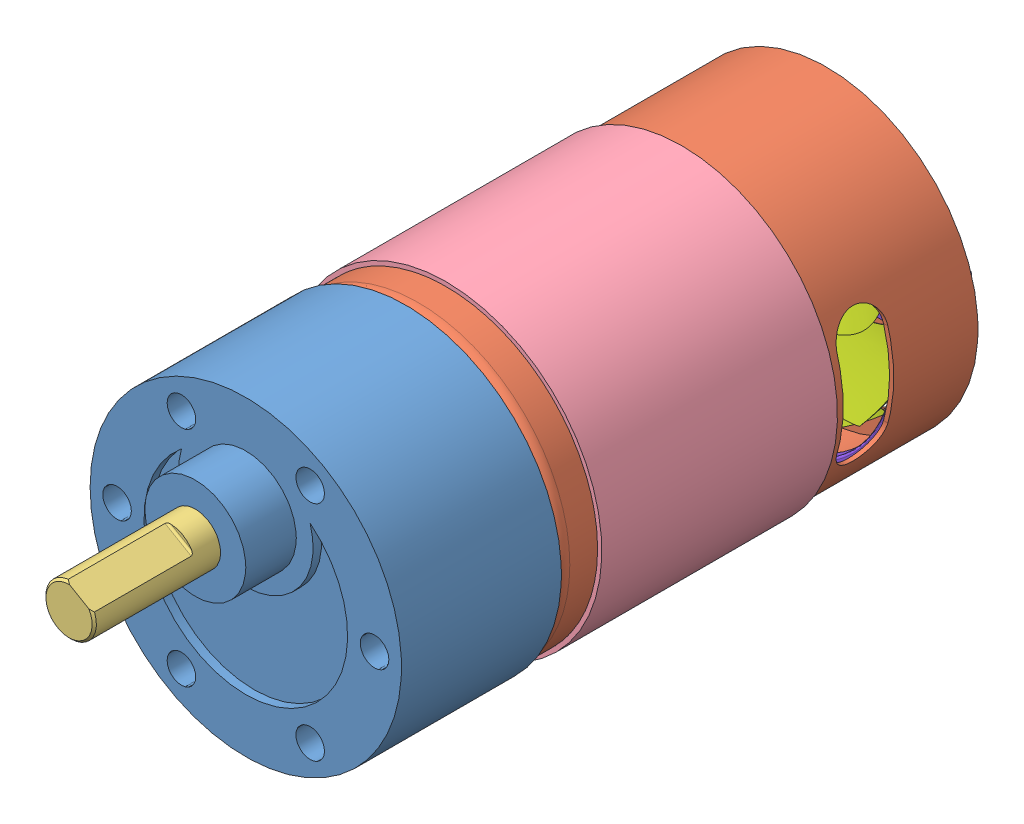
SolidWorks assembly Motor JGB37-545, configuration Predeterminado. Lengths in mm.
Overall size (41.44 41.14 94.88).
11 component instances, 11 part files, 33 mates.
Components (placement in the parent):
- Reduction box body-1: Reduction box body [Default] at (-12.375 1.5 54.875) size (37 37 25)
- Motor body-1: Motor body [Predeterminado] at (-12.375 1.5 4.875) size (36 36 52)
- Shaft-1: Shaft [Predeterminado] at (-12.375 8.5 67.775) x (0.863725 -0.503963 0) z (0 0 1) size (6 6 27.1)
- Cover-1: Cover [Predeterminado] at (-12.375 1.5 22.075) size (37 36.74 28)
- Rotor-1: Rotor [Predeterminado] at (-12.375 1.5 32.275) x (-0.951412 0.307919 0) z (0 0 1) size (26 25.6 60)
- Magnets-1: Magnets [Default] at (-12.375 1.5 22.875) x (0 1 0) z (0 0 1) size (35 27.22 20)
- Fan-1: Fan [Default] at (-12.375 1.5 12.975) x (-0.920955 0.389669 0) z (-0.389669 -0.920955 0) size (31.79 6.24 31.22)
- Terminals-1: Terminals [Default] at (-12.375 1.5 5.375) x (1 0 0) z (0 0 -1) size (34 34 22.88)
- Gear 1-1: Gear 1 [Default] at (-12.375 1.5 62.275) x (0.307919 0.951412 0) z (-0.951412 0.307919 0) size (5.97 2 5.97)
- Gear 2-1: Gear 2 [Default] at (-12.375 -3.65 64.275) x (0.994395 0.105729 0) z (-0.105729 0.994395 0) size (20 8.6 20)
- Gear 3-1: Gear 3 [Default] at (-12.375 8.5 66.275) x (-0.503963 -0.863725 0) z (0.863725 -0.503963 0) size (10 10 9.98)
Mates (geometry in assembly coordinates):
- Coincidente1: coincident anti-aligned: plane of Reduction box body-1 through (-12.375 1.5 54.875) normal (0 0 -1); plane of Motor body-1 through (-12.375 1.5 54.875) normal (0 0 1)
- Concéntrica1: concentric aligned: cylinder of Reduction box body-1 through (-12.375 1.5 73.875) axis (0 0 -1) radius 18.5; cylinder of Motor body-1 through (-12.375 1.5 54.875) axis (0 0 -1) radius 18
- Distancia1: distance = 15 mm aligned: plane of Shaft-1 through (-12.375 8.5 94.875) normal (0 0 1); plane of Reduction box body-1 through (-12.375 8.5 79.875) normal (0 0 1)
- Concéntrica2: concentric anti-aligned: cylinder of Reduction box body-1 through (-12.375 8.5 54.874) axis (0 0 1) radius 3; cylinder of Shaft-1 through (-12.375 8.5 94.875) axis (0 0 -1) radius 3
- Distancia2: distance = 4.8 mm anti-aligned: plane of Cover-1 through (-12.375 1.5 50.075) normal (0 0 1); plane of Reduction box body-1 through (-12.375 1.5 54.875) normal (0 0 -1)
- Concéntrica3: concentric aligned: cylinder of Motor body-1 through (-12.375 1.5 54.875) axis (0 0 -1) radius 18; cylinder of Cover-1 through (-12.375 1.5 50.075) axis (0 0 -1) radius 18
- Concentric1: concentric aligned: cylinder of Motor body-1 through (-12.375 1.5 54.875) axis (0 0 -1) radius 17.5; cylinder of Rotor-1 through (-12.375 1.5 30.875) axis (0 0 -1) radius 13
- Distance1: distance = 4 mm aligned: plane of Rotor-1 through (-9.5683 0.5916 8.875) normal (0 0 -1); plane of Motor-1 through (-12.375 1.5 4.875) normal (0 0 -1)
- Concentric3: concentric aligned: cylinder of Motor body-1 through (-12.375 1.5 54.875) axis (0 0 -1) radius 17.5; cylinder of Magnets-1 through (-12.375 1.5 42.875) axis (0 0 -1) radius 14.5
- Distance4: distance = 2 mm aligned: plane of magnets-1 through (-12.375 1.5 22.875) normal (0 0 -1); plane of Rotor-1 through (-12.375 1.5 24.875) normal (0 0 -1)
- Parallel2: parallel aligned: plane of Magnets-1 through (1.2357 6.5 42.875) normal (1 0 0)
- Coincident9: coincident anti-aligned: plane of Rotor-1 through (-12.375 1.5 9.375) normal (-0.951412 0.307919 0); plane of Fan-1 through (-13.2834 -1.3067 14.0996) normal (0.951412 -0.307919 0)
- Concentric5: concentric aligned: cylinder of Rotor-1 through (-12.375 1.5 62.275) axis (0 0 -1) radius 2; cylinder of Fan-1 through (-12.375 1.5 8.7004) axis (0 0 -1) radius 2
- Distance5: distance = 2 mm anti-aligned: plane of Rotor-1 through (-11.1255 -1.7502 14.975) normal (0 0 -1); plane of Fan-1 through (-12.375 1.5 12.975) normal (0 0 1)
- Coincident13: coincident anti-aligned: plane of Motor body-1 through (-25.125 -0.5 15.375) normal (0 1 0); plane of Terminals-1 through (-25.125 -0.5 4.875) normal (0 -1 0)
- Coincident14: coincident anti-aligned: plane of Motor body-1 through (0.375 3.5 15.375) normal (-1 0 0); plane of Terminals-1 through (0.375 -0.5 4.875) normal (1 0 0)
- Coincident15: coincident aligned: plane of Motor body-1 through (-12.375 -16 5.875) normal (0 0 1); plane of Terminals-1 through (-12.375 1.5 5.875) normal (0 0 1)
- Coincident16: coincident anti-aligned: plane of Terminals-1 through (-25.125 0.9005 0) normal (0 0 -1)
- Coincident17: coincident aligned: plane of Terminals-1 through (0 3 6.875) normal (1 0 0)
- Coincident18: coincident anti-aligned: plane of Terminals-1 through (-0.75 0 6.875) normal (0 -1 0)
- Parallel3: parallel anti-aligned: plane of Cover-1 through (-9.275 -16.231 50.075) normal (-1 0 0)
- Parallel4: parallel aligned: plane of Reduction box body-1 through (-18.625 -12.75 55.025) normal (1 0 0)
- Concentric6: concentric anti-aligned: cylinder of Rotor-1 through (-12.375 1.5 62.275) axis (0 0 -1) radius 2; cylinder of Gear 1-1 through (-12.375 1.5 60.275) axis (0 0 1) radius 2
- Coincident19: coincident anti-aligned: plane of Rotor-1 through (-12.8369 0.0729 56.275) normal (-0.307919 -0.951412 0); plane of Gear 1-1 through (-12.8369 0.0729 60.275) normal (0.307919 0.951412 0)
- Coincident26: coincident aligned: plane of Rotor-1 through (-12.375 1.5 62.275) normal (0 0 1); plane of Gear 1-1 through (-12.375 1.5 62.275) normal (0 0 1)
- Concentric7: concentric anti-aligned: cylinder of Shaft-1 through (-12.375 8.5 94.875) axis (0 0 -1) radius 3; cylinder of Gear 5-1 through (-12.375 8.5 64.275) axis (0 0 1) radius 5
- Coincident23: coincident anti-aligned: plane of Shaft-1 through (-11.997 9.1478 70.275) normal (-0.503963 -0.863725 0); plane of Gear 5-1 through (-11.997 9.1478 67.775) normal (0.503963 0.863725 0)
- Coincident24: coincident anti-aligned: plane of Shaft-1 through (-12.375 8.5 70.275) normal (0 0 -1); plane of Gear 5-1 through (-12.375 8.5 70.275) normal (0 0 1)
- Parallel5: parallel anti-aligned: plane of Shaft-1 through (-12.375 8.5 94.875) normal (0 0 1); plane of Gear 2-1 through (-12.375 -3.65 58.275) normal (0 0 -1)
- Coincident27: coincident aligned: plane of Gear 1-1 through (-12.375 1.5 60.275) normal (0 0 -1); plane of Gear 2-1 through (-12.375 -3.65 60.275) normal (0 0 -1)
- Concentric9: concentric aligned: cylinder of Reduction box body-1 through (-12.375 -3.65 65.875) axis (0 0 1) radius 2; cylinder of Gear 2-1 through (-12.375 -3.65 58.275) axis (0 0 1) radius 1
- GearMate2: gear = 28 : 23 mm: cylinder of Gear 2-1 through (-12.375 -3.65 60.275) axis (0 0 1) radius 2.5; cylinder of Gear 1-1 through (-12.375 1.5 60.275) axis (0 0 1) radius 3
- GearMate3: gear = 23 : 100 mm: cylinder of Gear 2-1 through (-12.375 -3.65 64.275) axis (0 0 -1) radius 10; cylinder of Gear 3-1 through (-12.375 8.5 62.275) axis (0 0 1) radius 2.5
